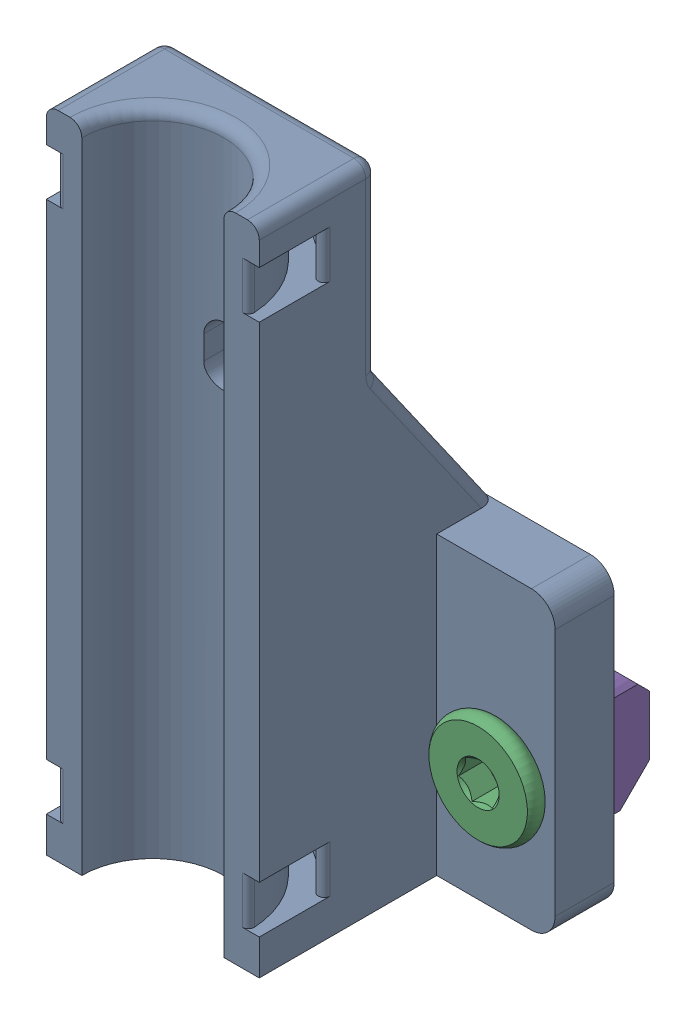
SolidWorks assembly tool_cable_management_assembly, configuration Default. Lengths in mm.
Overall size (40.2 55.06 25).
5 component instances, 3 part files, 0 mates.
Components (placement in the parent):
- tool_cable_management_bracket-1: tool_cable_management_bracket [Default] at (1.9041 354.0105 503.3157) x (-1 0 0) z (0 0 -1) size (38 55.06 20)
- m5_low_profile_screw_template_M5 x 10-1: m5_low_profile_screw_template_M5 x 10 [Default] at (-12.0959 364.0105 498.3157) x (0 0 -1) z (0.928561 0.37118 0) size (11.62 9 9)
- m5_low_profile_screw_template_M5 x 10-2: m5_low_profile_screw_template_M5 x 10 [Default] at (15.9041 364.0105 498.3157) x (0 0 -1) z (0.757132 0.653262 0) size (11.62 9 9)
- m5_locking_t_nut_20x20_generic-1: m5_locking_t_nut_20x20_generic [Default] at (-9.0959 364.0105 498.3157) x (0 -1 0) z (-1 0 0) size (10 4.5 6)
- m5_locking_t_nut_20x20_generic-2: m5_locking_t_nut_20x20_generic [Default] at (18.9041 364.0105 498.3157) x (0 -1 0) z (-1 0 0) size (10 4.5 6)
